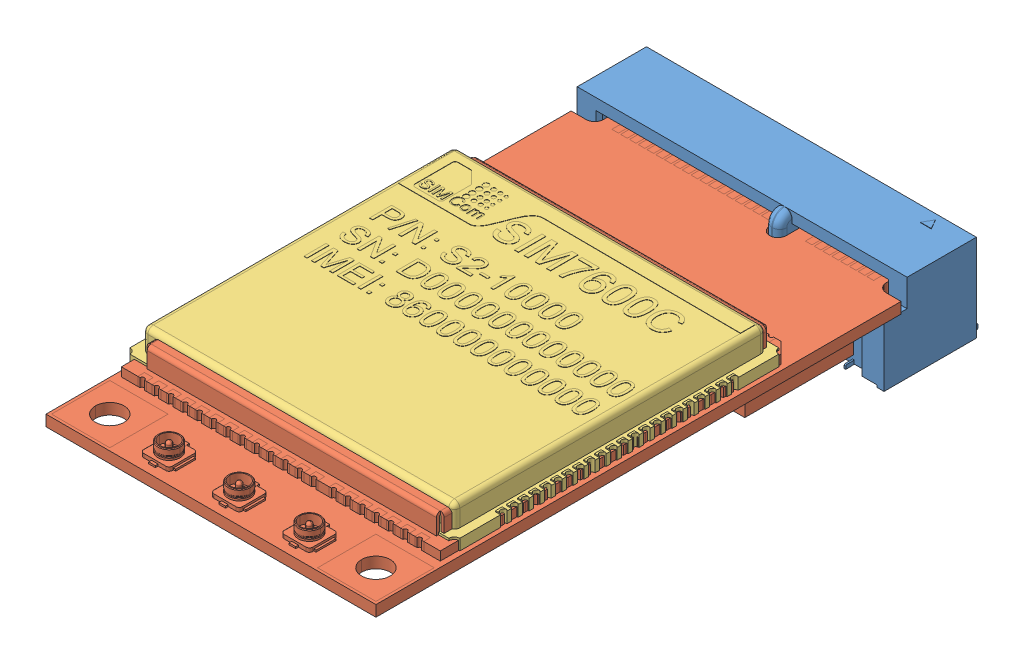
SolidWorks assembly Final_MiniPCIE, configuration Default. Lengths in mm.
Overall size (30.41 10.25 55.57).
4 component instances, 3 part files, 1 mates.
Components (placement in the parent):
- Final_MiniPCIE.STEP-1: Final_MiniPCIE.STEP [Default] at origin size (30.15 9.77 55.57)
  - 1759503-1.stp.STEP-1: 1759503-1.stp.STEP [Default] at (8.4189 17.4457 28.1156) size (30 8.68 9.22)
  - Card_mini.STEP-1: Card_mini.STEP [Default] at (8.5689 19.4407 23.5156) x (-1 0 0) z (0 1 0) size (30 50.95 4.9)
- SIM7600C.step-1: SIM7600C.step [Default] at (8.1609 19.8407 51.9299) size (30 3.17 30)
Mates (geometry in assembly coordinates):
- Coincident1: coincident anti-aligned: plane of Final_MiniPCIE.STEP-1/Card_mini.STEP-1 through (-5.0811 19.9407 25.9156) normal (0 1 0); plane of SIM7600C.step-1 through (8.1609 19.9407 51.9299) normal (0 -1 0)
